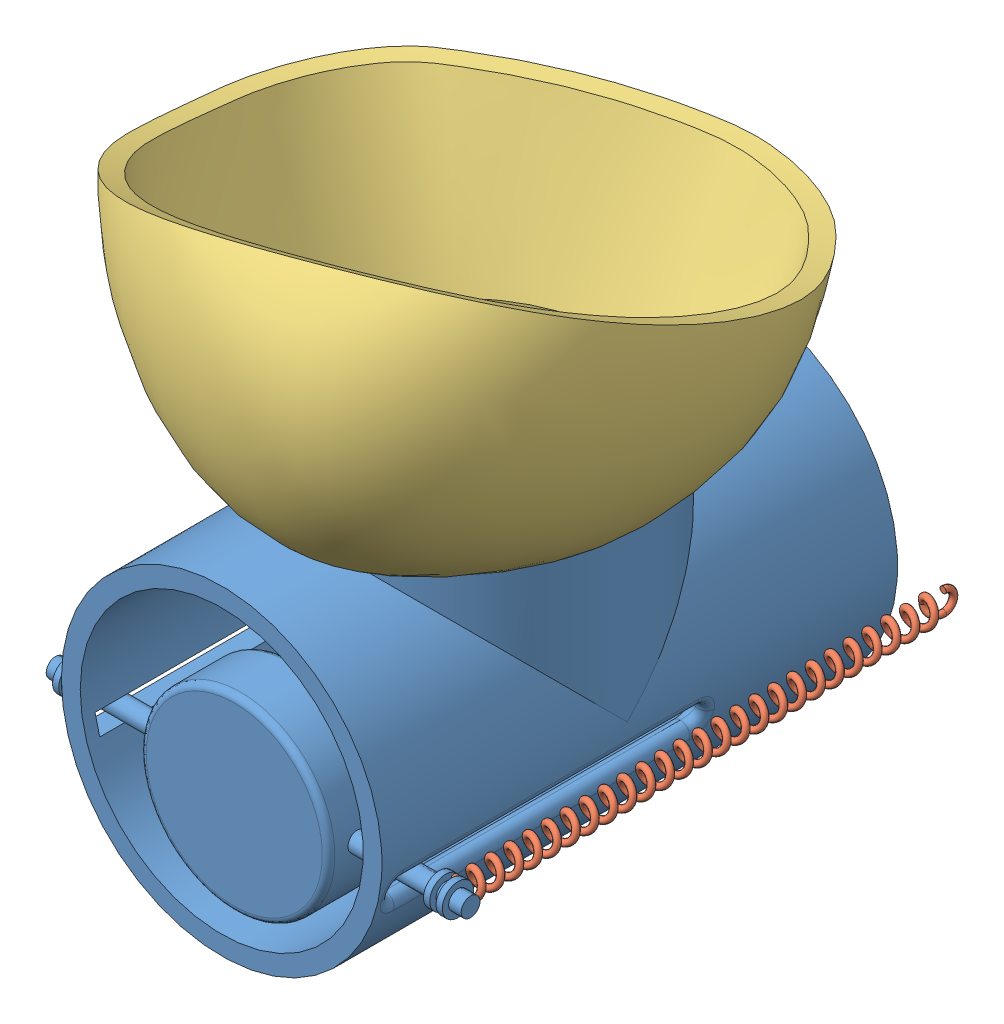
SolidWorks assembly spring assembly to the cylinder_11.06pm, configuration Default. Lengths in mm.
Overall size (116.81 106.15 115.05).
4 component instances, 3 part files, 6 mates.
Components (placement in the parent):
- bottom part-1: bottom part [Default] at (16.4612 51.9827 29.7161) size (66 51.5 82)
- spring-1: spring [Default] at (46.4612 46.5132 103.532) x (0 0.999821 0.018905) z (-1 0 0) size (5.47 82.4 5.47)
- spring-3: spring [Default] at (-13.5388 46.4913 103.5318) x (0 -0.999986 -0.005211) z (1 0 0) size (5.47 82.4 5.47)
- funnel-1: funnel [Default] at (16.4612 127.9827 72.7161) x (0.358061 0 0.933698) z (0.933698 0 -0.358061) size (88.22 55.15 91.27)
Mates (geometry in assembly coordinates):
- Concentric1: concentric aligned: cylinder of bottom part-1 through (-16.5388 46.483 105.1317) axis (1 0 0) radius 1.5; circle of spring-1
- Concentric2: concentric anti-aligned: circle of bottom part-1; circle of spring-1
- Coincident1: coincident anti-aligned: plane of bottom part-1 through (46.4612 46.483 105.1317) normal (-1 0 0); circle of spring-1
- Concentric4: concentric anti-aligned: cylinder of bottom part-1 through (-16.5388 46.483 105.1317) axis (1 0 0) radius 1.5; circle of spring-3
- Coincident2: coincident anti-aligned: plane of bottom part-1 through (-13.5388 46.483 105.1317) normal (1 0 0); circle of spring-3
- Coincident3: coincident anti-aligned: circle of bottom part-1; circle of funnel-1
